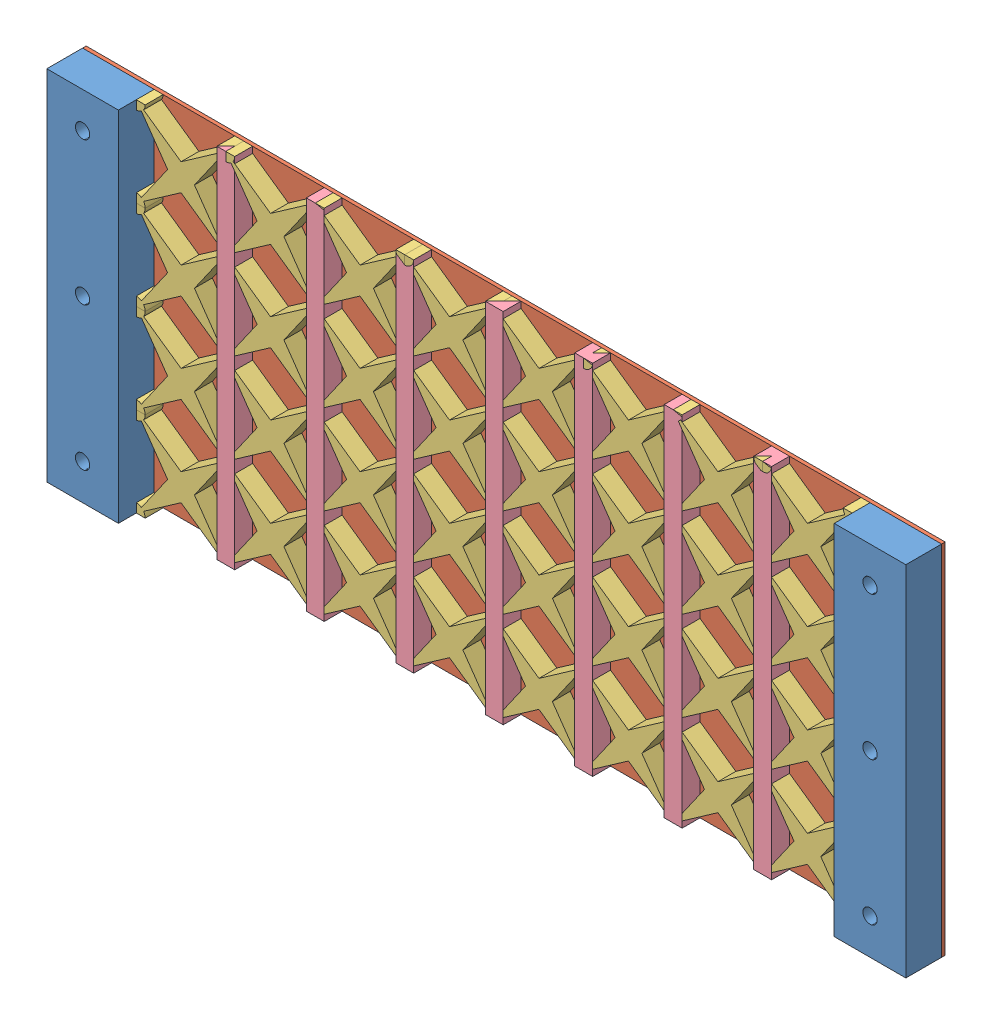
SolidWorks assembly 3DhoneyAssem, configuration Honeycomb. Lengths in mm.
Overall size (240 100 11).
50 component instances, 4 part files, 11 mates.
Components (placement in the parent):
- Frame-1: Frame [Default] at origin size (240 100 10)
- AirfoilBacking-1: AirfoilBacking [Default] x (-1 0 0) z (0 0 -1) size (240 100 1)
- StarHoneycomb-1: StarHoneycomb [Default] at (175 0 0) size (25 25 5)
- StarHoneycomb-2: StarHoneycomb [1:2 Ratio] at (150 0 0) (suppressed, hidden)
- StarHoneycomb-3: StarHoneycomb [1:2 Ratio] at (125 0 0) (suppressed, hidden)
- StarHoneycomb-4: StarHoneycomb [1:2 Ratio] at (100 0 0) (suppressed, hidden)
- StarHoneycomb-5: StarHoneycomb [1:2 Ratio] at (75 0 0) (suppressed, hidden)
- StarHoneycomb-6: StarHoneycomb [1:2 Ratio] at (50 0 0) (suppressed, hidden)
- StarHoneycomb-7: StarHoneycomb [1:2 Ratio] at (25 0 0) (suppressed, hidden)
- StarHoneycomb-8: StarHoneycomb [1:2 Ratio] at origin (suppressed, hidden)
- StarHoneycomb-9: StarHoneycomb [1:2 Ratio] at (175 50 0) (suppressed, hidden)
- StarHoneycomb-10: StarHoneycomb [1:2 Ratio] at (150 50 0) (suppressed, hidden)
- StarHoneycomb-11: StarHoneycomb [1:2 Ratio] at (125 50 0) (suppressed, hidden)
- StarHoneycomb-12: StarHoneycomb [1:2 Ratio] at (100 50 0) (suppressed, hidden)
- StarHoneycomb-13: StarHoneycomb [1:2 Ratio] at (75 50 0) (suppressed, hidden)
- StarHoneycomb-14: StarHoneycomb [1:2 Ratio] at (50 50 0) (suppressed, hidden)
- StarHoneycomb-15: StarHoneycomb [1:2 Ratio] at (25 50 0) (suppressed, hidden)
- StarHoneycomb-16: StarHoneycomb [1:2 Ratio] at (0 50 0) (suppressed, hidden)
- HoneyCombBeam^3DhoneyAssem-1: HoneyCombBeam^3DhoneyAssem [Default] at (0 100 0) x (1 0 0) z (0 1 0) size (155 5 100) (virtual)
- StarHoneycomb-33: StarHoneycomb [Default] at (150 0 0) size (25 25 5)
- StarHoneycomb-34: StarHoneycomb [Default] at (125 0 0) size (25 25 5)
- StarHoneycomb-35: StarHoneycomb [Default] at (100 0 0) size (25 25 5)
- StarHoneycomb-36: StarHoneycomb [Default] at (75 0 0) size (25 25 5)
- StarHoneycomb-37: StarHoneycomb [Default] at (50 0 0) size (25 25 5)
- StarHoneycomb-38: StarHoneycomb [Default] at (25 0 0) size (25 25 5)
- StarHoneycomb-39: StarHoneycomb [Default] at origin size (25 25 5)
- StarHoneycomb-40: StarHoneycomb [Default] at (175 25 0) size (25 25 5)
- StarHoneycomb-41: StarHoneycomb [Default] at (150 25 0) size (25 25 5)
- StarHoneycomb-42: StarHoneycomb [Default] at (125 25 0) size (25 25 5)
- StarHoneycomb-43: StarHoneycomb [Default] at (100 25 0) size (25 25 5)
- StarHoneycomb-44: StarHoneycomb [Default] at (75 25 0) size (25 25 5)
- StarHoneycomb-45: StarHoneycomb [Default] at (50 25 0) size (25 25 5)
- StarHoneycomb-46: StarHoneycomb [Default] at (25 25 0) size (25 25 5)
- StarHoneycomb-47: StarHoneycomb [Default] at (0 25 0) size (25 25 5)
- StarHoneycomb-48: StarHoneycomb [Default] at (175 50 0) size (25 25 5)
- StarHoneycomb-49: StarHoneycomb [Default] at (150 50 0) size (25 25 5)
- StarHoneycomb-50: StarHoneycomb [Default] at (125 50 0) size (25 25 5)
- StarHoneycomb-51: StarHoneycomb [Default] at (100 50 0) size (25 25 5)
- StarHoneycomb-52: StarHoneycomb [Default] at (75 50 0) size (25 25 5)
- StarHoneycomb-53: StarHoneycomb [Default] at (50 50 0) size (25 25 5)
- StarHoneycomb-54: StarHoneycomb [Default] at (25 50 0) size (25 25 5)
- StarHoneycomb-55: StarHoneycomb [Default] at (0 50 0) size (25 25 5)
- StarHoneycomb-56: StarHoneycomb [Default] at (175 75 0) size (25 25 5)
- StarHoneycomb-57: StarHoneycomb [Default] at (150 75 0) size (25 25 5)
- StarHoneycomb-58: StarHoneycomb [Default] at (125 75 0) size (25 25 5)
- StarHoneycomb-59: StarHoneycomb [Default] at (100 75 0) size (25 25 5)
- StarHoneycomb-60: StarHoneycomb [Default] at (75 75 0) size (25 25 5)
- StarHoneycomb-61: StarHoneycomb [Default] at (50 75 0) size (25 25 5)
- StarHoneycomb-62: StarHoneycomb [Default] at (25 75 0) size (25 25 5)
- StarHoneycomb-63: StarHoneycomb [Default] at (0 75 0) size (25 25 5)
Mates (geometry in assembly coordinates):
- InPlace1: in place: plane of ? through (0 0 0) normal (0 0 -1); plane of AirfoilBacking-1 through (0 0 0) normal (0 0 -1); moOrthogonalPlaneRef_w of ? through (0 0 0) normal (0 0 -1); plane of AirfoilBacking-1 through (0 0 0) normal (0 1 0); plane of ? through (0 0 0) normal (0 0 -1); plane of AirfoilBacking-1 through (0 0 0) normal (-1 0 0); plane of ? through (0 0 0) normal (0 0 -1); unknown of AirfoilBacking-1
- Coincident1: coincident aligned: plane of ?; plane of ?
- Coincident2: coincident aligned: moOrthogonalPlaneRef_w of Frame-1 through (0 0 0) normal (0 1 0); plane of Part2^3DhoneyAssem-1 through (0 0 0) normal (0 1 0)
- Coincident3: coincident anti-aligned: moOrthogonalPlaneRef_w of Frame-1 through (0 0 0) normal (1 0 0); plane of Part2^3DhoneyAssem-1 through (0 0 0) normal (-1 0 0)
- Coincident4: coincident anti-aligned: plane of Frame-1 through (200 0 10) normal (-1 0 0); plane of StarHoneycomb-1 through (200 2.5 -3.5355) normal (1 0 0)
- Coincident5: coincident aligned: plane of Frame-1 through (200 0 10) normal (0 -1 0); plane of StarHoneycomb-1 through (200 0 -3.5355) normal (0 -1 0)
- Coincident7: coincident aligned: plane of Frame-1 through (0 0 0) normal (0 0 -1); plane of StarHoneycomb-1 through (175 0 0) normal (0 0 -1)
- InPlace3: in place: plane of ? through (-20 100 10) normal (0 1 0); plane of HoneyCombBeam^3DhoneyAssem-1 through (0 100 0) normal (0 1 0); plane of ? through (-20 100 10) normal (0 1 0); plane of HoneyCombBeam^3DhoneyAssem-1 through (0 100 0) normal (0 0 -1); plane of ? through (-20 100 10) normal (0 1 0); plane of HoneyCombBeam^3DhoneyAssem-1 through (0 100 0) normal (1 0 0); plane of ? through (-20 100 10) normal (0 1 0); unknown of HoneyCombBeam^3DhoneyAssem-1
- Coincident8: coincident aligned: plane of ?; plane of ?
- Coincident9: coincident aligned: moOrthogonalPlaneRef_w of Frame-1 through (0 100 0) normal (0 0 -1); plane of HoneyCombBeam^3DhoneyAssem-1 through (0 100 0) normal (0 0 -1)
- Coincident10: coincident anti-aligned: moOrthogonalPlaneRef_w of Frame-1 through (0 100 0) normal (-1 0 0); plane of HoneyCombBeam^3DhoneyAssem-1 through (0 100 0) normal (1 0 0)
